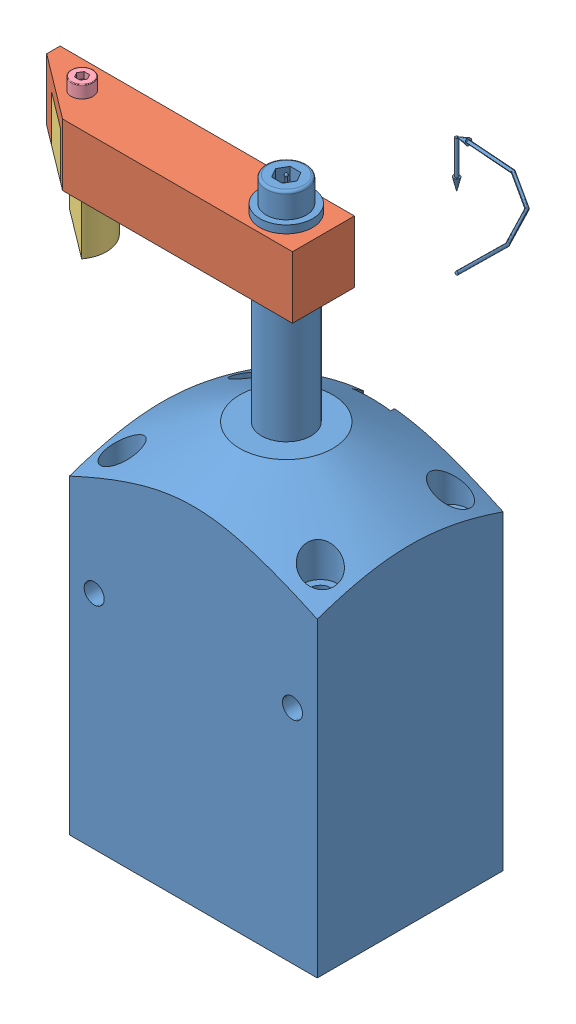
SolidWorks assembly assemb_pneu_clamp_v2, configuration Default. Lengths in mm.
Overall size (138.53 190.01 86.05).
9 component instances, 4 part files, 6 mates.
Components (placement in the parent):
- clamping_body_ccw-1: clamping_body_ccw [Default] at (55.286 179.8503 172.3742) x (-1 0 0) z (0 1 0) size (95.58 86.05 190.01)
- assemb_braco_v2-1: assemb_braco_v2 [Default] at (45.4961 98.2616 242.6188) x (-1 0 0) z (0 0 -1) size (95 44 24)
  - clamping_arm_sp_v2-1: clamping_arm_sp_v2 [Default] at (-9.7899 71.0887 70.2446) x (1 0 0) z (0 1 0) size (95 20 20) (hidden)
  - contact_end_spec-1: contact_end_spec [Default] at (58.2101 31.0887 70.2446) x (0.601815 0 -0.798636) z (0.798636 0 0.601815) size (14.5 35 20) (hidden)
  - socket head cap screw_iso-1: socket head cap screw_iso [ISO 4762 M4 x 16 - 16N] at (57.3074 75.0887 71.4426) x (0 -1 0) z (0 0 1) size (20 7 7) (hidden)
- assemb_braco_v2-2: assemb_braco_v2 [Default] at (125.5306 68.2616 182.1641) x (0 0 1) z (-1 0 0) size (95 44 24)
  - clamping_arm_sp_v2-1: clamping_arm_sp_v2 [Default] at (-9.7899 71.0887 70.2446) x (1 0 0) z (0 1 0) size (95 20 20) (hidden)
  - contact_end_spec-1: contact_end_spec [Default] at (58.2101 31.0887 70.2446) x (0.601815 0 -0.798636) z (0.798636 0 0.601815) size (14.5 35 20) (hidden)
  - socket head cap screw_iso-1: socket head cap screw_iso [ISO 4762 M4 x 16 - 16N] at (57.3074 75.0887 71.4426) x (0 -1 0) z (0 0 1) size (20 7 7) (hidden)
Mates (geometry in assembly coordinates):
- Concentric1: concentric aligned: cone of clamping_body_ccw-1 through (55.286 167.3503 172.3742) axis (0 1 0); cone of assemb_braco_v2-1/clamping_arm_sp_v2-1 through (55.286 169.3503 172.3742) axis (0 1 0)
- Parallel1: parallel aligned: plane of clamping_body_ccw-1 through (15.286 110.8503 142.3742) normal (-1 0 0); plane of assemb_braco_v2-1/clamping_arm_sp_v2-1 through (-27.714 149.3503 182.3742) normal (-1 0 0)
- Coincident2: coincident aligned: circle of clamping_body_ccw-1; plane of assemb_braco_v2-1/clamping_arm_sp_v2-1 through (67.286 149.3503 162.3742) normal (0 -1 0)
- Concentric2: concentric anti-aligned: cylinder of clamping_body_ccw-1 through (55.286 109.8716 172.3742) axis (0 -1 0) radius 8; cone of assemb_braco_v2-2/clamping_arm_sp_v2-1 through (55.286 139.3503 172.3742) axis (0 1 0)
- Parallel3: parallel aligned: plane of clamping_body_ccw-1 through (95.286 110.8503 202.3742) normal (0 0 1); plane of assemb_braco_v2-2/clamping_arm_sp_v2-1 through (65.286 119.3503 255.3742) normal (0 0 1)
- Distance2: distance = 30 mm aligned: plane of assemb_braco_v2-2/clamping_arm_sp_v2-1 through (45.286 139.3503 160.3742) normal (0 1 0); plane of assemb_braco_v2-1/clamping_arm_sp_v2-1 through (67.286 169.3503 162.3742) normal (0 1 0)
